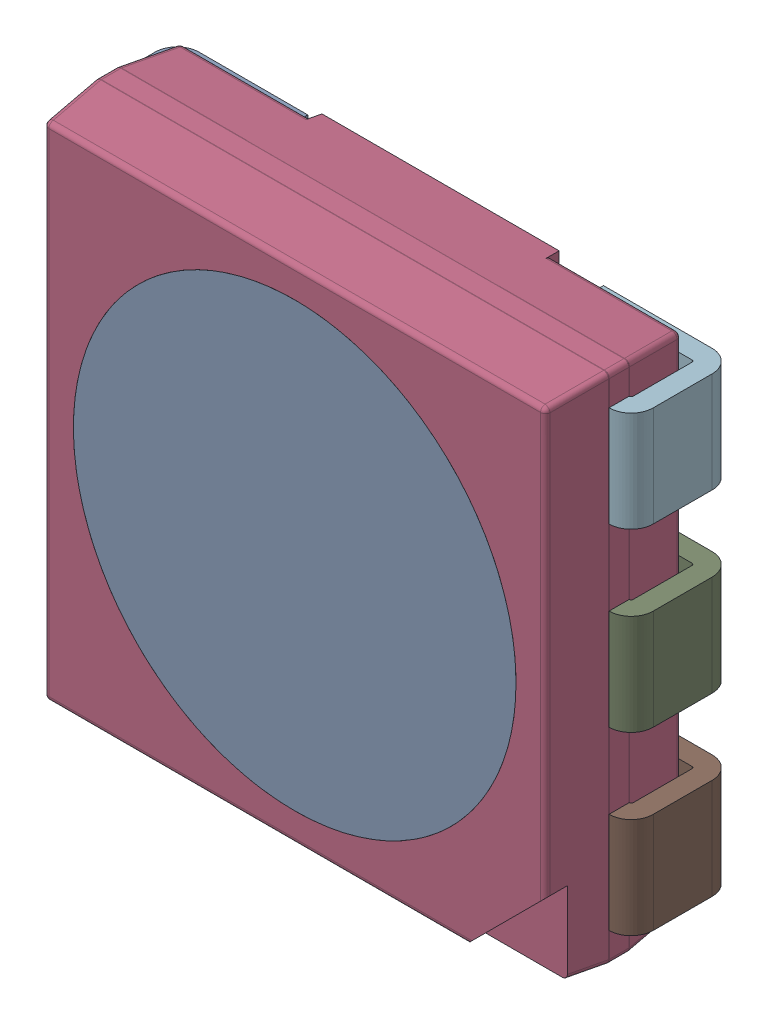
SolidWorks assembly User Library-5050 RGB led, configuration Default. Lengths in mm.
Overall size (5.54 5.1 1.61).
9 component instances, 2 part files, 0 mates.
Components (placement in the parent):
- User Library-5050 RGB led_7252440064-1: User Library-5050 RGB led_7252440064 [Default] at (0.0001 0 0) size (5.54 5.1 1.61)
  - User Library-5050 RGB led_Body-1: User Library-5050 RGB led_Body [Default] at (-2.55 -2.55 0.25) size (5.1 5.1 1.46)
    - 1-1: 1 [Default] at origin size (5.1 5.1 1.46)
  - User Library-5050 RGB led_Lead-1: User Library-5050 RGB led_Lead [Default] at (1.47 0 0) size (1.3 1 1.03)
  - User Library-5050 RGB led_Lead-2: User Library-5050 RGB led_Lead [Default] at (-1.47 0 0) x (-1 0 0) z (0 0 1) size (1.3 1 1.03)
  - User Library-5050 RGB led_Lead-3: User Library-5050 RGB led_Lead [Default] at (1.47 -1.75 0) size (1.3 1 1.03)
  - User Library-5050 RGB led_Lead-4: User Library-5050 RGB led_Lead [Default] at (1.47 1.75 0) size (1.3 1 1.03)
  - User Library-5050 RGB led_Lead-5: User Library-5050 RGB led_Lead [Default] at (-1.47 1.75 0) x (-1 0 0) z (0 0 1) size (1.3 1 1.03)
  - User Library-5050 RGB led_Lead-6: User Library-5050 RGB led_Lead [Default] at (-1.47 -1.75 0) x (-1 0 0) z (0 0 1) size (1.3 1 1.03)
